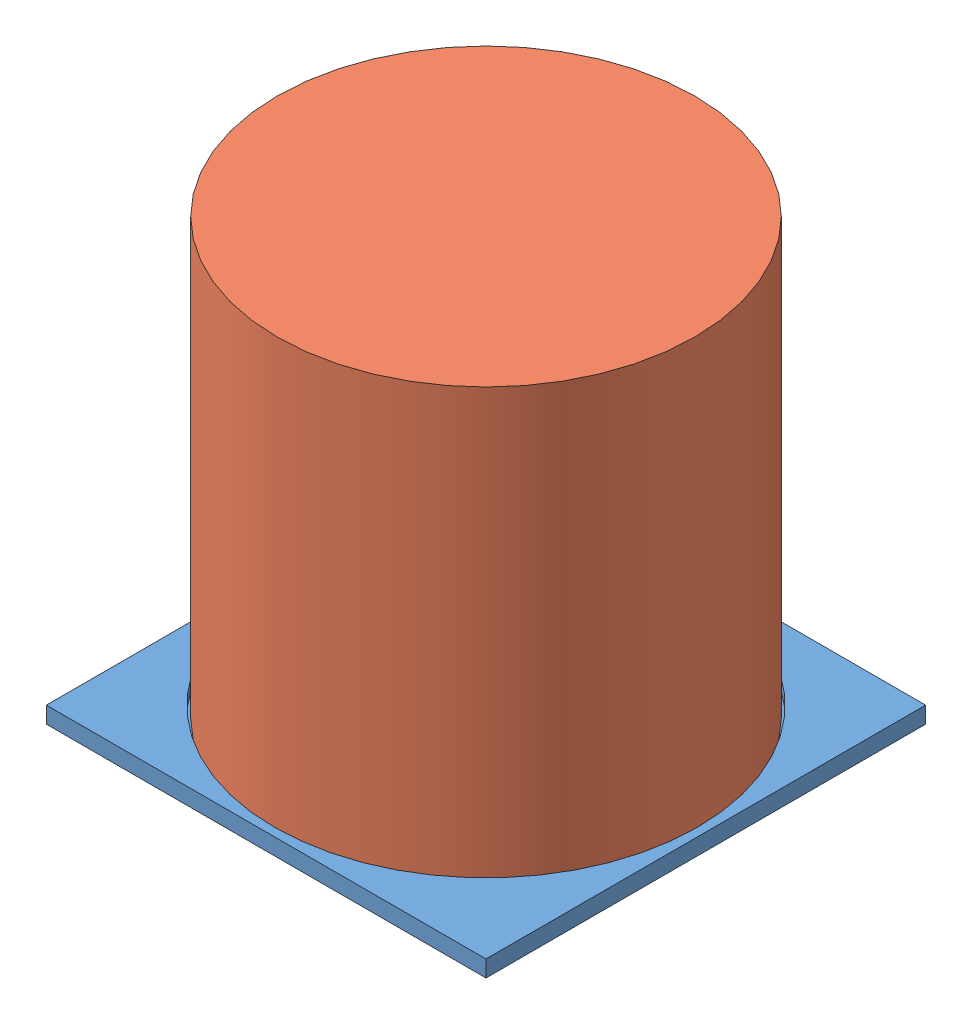
SolidWorks assembly Balises_passives_v2, configuration Default. Lengths in mm.
Overall size (80 80 80).
2 component instances, 2 part files, 2 mates.
Components (placement in the parent):
- support-1: support [Default] at (-25.4422 3.857 10.8051) size (80 3 80)
- cylindre-1: cylindre [Default] at (14.5578 4.857 10.8051) size (76 79 76)
Mates (geometry in assembly coordinates):
- Coincident1: coincident: plane of support-1 through (14.5578 4.857 10.8051) normal (0 1 0); plane of cylindre-1 through (14.5578 4.857 10.8051) normal (0 -1 0)
- Concentric1: concentric anti-aligned: circle of support-1; cylinder of cylindre-1 through (14.5578 83.857 10.8051) axis (0 -1 0) radius 38
